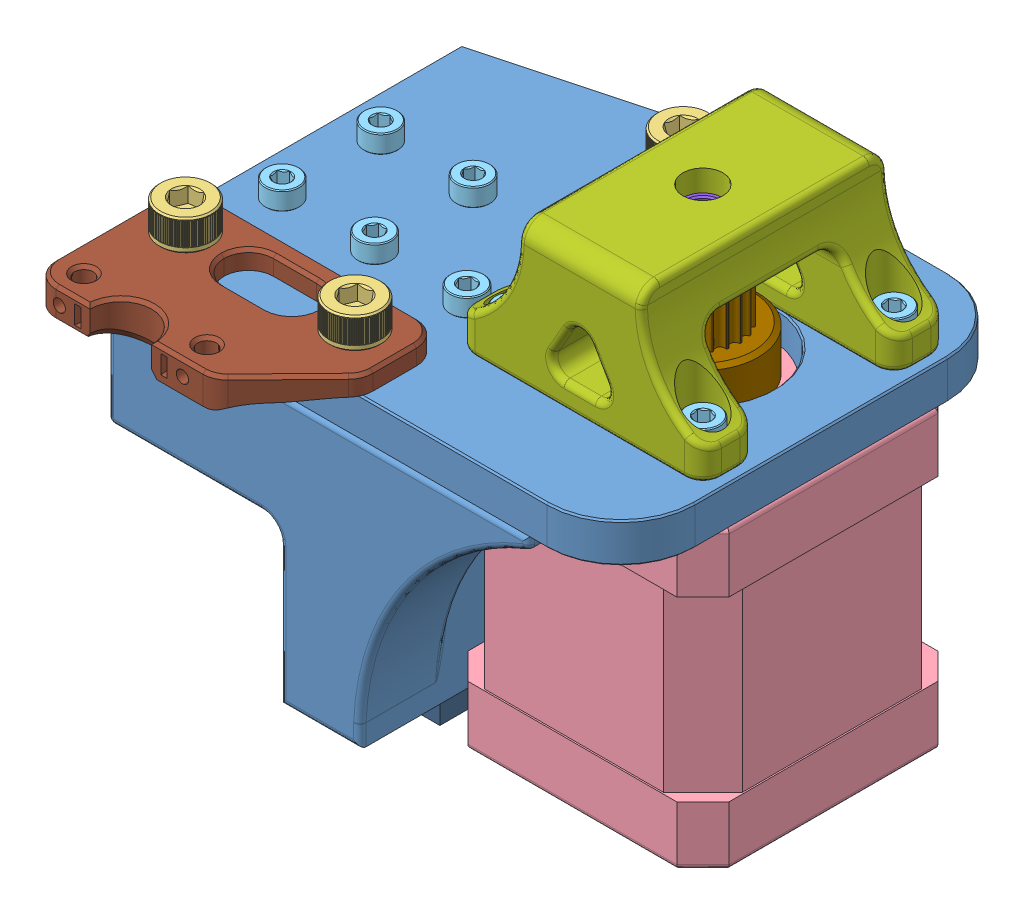
SolidWorks assembly x_motor, configuration Default. Lengths in mm.
Overall size (83.4 79.09 77.36).
24 component instances, 11 part files, 50 mates.
Components (placement in the parent):
- x_axis_motor_mount-1: x_axis_motor_mount [Default] at (11.6499 65.9812 53.7622) size (83.4 49.95 65.06)
- 94180A361_Tapered Heat-Set Inserts for Plastic-2: 94180A361_Tapered Heat-Set Inserts for Plastic [94180A361] at (18.6499 80.6162 113.0622) x (0.881944 0 0.471354) z (0 1 0) size (8.33 8.33 7.05)
- 94180A361_Tapered Heat-Set Inserts for Plastic-3: 94180A361_Tapered Heat-Set Inserts for Plastic [94180A361] at (46.1499 80.6162 113.0622) x (0.881944 0 0.471354) z (0 1 0) size (8.33 8.33 7.05)
- 94180A361_Tapered Heat-Set Inserts for Plastic-4: 94180A361_Tapered Heat-Set Inserts for Plastic [94180A361] at (46.1499 80.6162 59.7622) x (0.881944 0 0.471354) z (0 1 0) size (8.33 8.33 7.05)
- 91290A231_Alloy Steel Socket Head Screw-4: 91290A231_Alloy Steel Socket Head Screw [91290A231] at (46.1499 85.3312 59.7622) x (-0.423416 0 -0.905935) z (0 1 0) size (8.5 8.5 20.34)
- 6627T91_Stepper Motor-1: 6627T91_Stepper Motor [6627T91] at (73.8499 71.9942 84.2622) x (1 0 0) z (0 1 0) size (42.4 43.16 72.04)
- 91290A572_Black-Oxide Alloy Steel Socket Head Screw-8: 91290A572_Black-Oxide Alloy Steel Socket Head Screw [30] at (33.6499 76.8312 81.3622) x (-0.098871 0 -0.9951) z (0 1 0) size (5.5 5.5 33.14)
- 91290A572_Black-Oxide Alloy Steel Socket Head Screw-9: 91290A572_Black-Oxide Alloy Steel Socket Head Screw [30] at (18.6499 76.8312 81.3622) x (0.520474 0 -0.853877) z (0 1 0) size (5.5 5.5 33.14)
- 94180A331_Tapered Heat-Set Inserts for Plastic-6: 94180A331_Tapered Heat-Set Inserts for Plastic [94180A331] at (46.1499 42.2812 86.2622) x (0.757966 0 -0.652294) z (0 -1 0) size (5.56 5.56 3.99)
- 91290A572_Black-Oxide Alloy Steel Socket Head Screw-13: 91290A572_Black-Oxide Alloy Steel Socket Head Screw [10] at (46.1499 40.8812 86.2622) x (0.101337 0 0.994852) z (0 -1 0) size (5.5 5.5 13.14)
- motor_bearing_support-1: motor_bearing_support [Default] at (73.8499 90.3312 84.2622) x (0 0 -1) z (0 1 0) size (40 40 23)
- 6153K69_Stainless Steel Ball Bearing-2: 6153K69_Stainless Steel Ball Bearing [6153K69] at (73.8499 107.3312 84.2622) x (0.996052 0 -0.088777) z (0 1 0) size (16 16 5)
- 91290A572_Black-Oxide Alloy Steel Socket Head Screw-20: 91290A572_Black-Oxide Alloy Steel Socket Head Screw [30] at (18.6499 76.8312 97.3622) x (0.989261 0 -0.146162) z (0 1 0) size (5.5 5.5 33.14)
- 91290A572_Black-Oxide Alloy Steel Socket Head Screw-21: 91290A572_Black-Oxide Alloy Steel Socket Head Screw [30] at (33.6499 76.8312 97.3622) x (0.062138 0 -0.998068) z (0 1 0) size (5.5 5.5 33.14)
- 91290A572_Black-Oxide Alloy Steel Socket Head Screw-22: 91290A572_Black-Oxide Alloy Steel Socket Head Screw [30] at (48.6498 76.8312 97.3622) x (0.062138 0 -0.998068) z (0 1 0) size (5.5 5.5 33.14)
- 91290A572_Black-Oxide Alloy Steel Socket Head Screw-24: 91290A572_Black-Oxide Alloy Steel Socket Head Screw [15mm] at (89.3499 87.3312 68.7622) x (-0.351895 0 0.936039) z (0 1 0) size (5.5 5.5 18.14)
- 91290A572_Black-Oxide Alloy Steel Socket Head Screw-25: 91290A572_Black-Oxide Alloy Steel Socket Head Screw [15mm] at (58.3499 87.3312 68.7622) x (-0.351895 0 0.936039) z (0 1 0) size (5.5 5.5 18.14)
- 91290A572_Black-Oxide Alloy Steel Socket Head Screw-26: 91290A572_Black-Oxide Alloy Steel Socket Head Screw [15mm] at (89.3499 87.3312 99.7622) x (-0.351895 0 0.936039) z (0 1 0) size (5.5 5.5 18.14)
- 91290A572_Black-Oxide Alloy Steel Socket Head Screw-27: 91290A572_Black-Oxide Alloy Steel Socket Head Screw [15mm] at (58.3499 87.3312 99.7622) x (-0.351895 0 0.936039) z (0 1 0) size (5.5 5.5 18.14)
- 3684N13_Corrosion-Resistant HTD Timing Belt Pulley-1: 3684N13_Corrosion-Resistant HTD Timing Belt Pulley [3684N13] at (73.8499 94.0132 84.2622) x (-0.88266 0 0.470012) z (0 1 0) size (18 18 18)
- belp_grip-3: belp_grip [Default] at (46.1499 37.3812 86.2622) x (0 0 1) z (-1 0 0) size (39 3 13)
- y_axis_strain_relief-1: y_axis_strain_relief [Default] at (11.6499 90.3312 106.0622) size (41.5 9.35 25)
- 91290A231_Alloy Steel Socket Head Screw-10: 91290A231_Alloy Steel Socket Head Screw [91290A231] at (18.6499 88.3312 113.0622) x (0.923345 0 0.38397) z (0 1 0) size (8.5 8.5 20.34)
- 91290A231_Alloy Steel Socket Head Screw-11: 91290A231_Alloy Steel Socket Head Screw [91290A231] at (46.1499 88.3312 113.0622) x (0.923345 0 0.38397) z (0 1 0) size (8.5 8.5 20.34)
Mates (geometry in assembly coordinates):
- Concentric11: concentric aligned: cylinder of x_axis_motor_mount-1 through (18.6499 71.9812 113.0622) axis (0 1 0) radius 3.25; cylinder of 94180A361_Tapered Heat-Set Inserts for Plastic-2 through (18.6499 83.9812 113.0622) axis (0 1 0) radius 4.165
- Coincident11: coincident aligned: plane of x_axis_motor_mount-1 through (80.0499 83.9812 105.4622) normal (0 1 0); plane of 94180A361_Tapered Heat-Set Inserts for Plastic-2 through (19.8283 83.9812 110.8573) normal (0 1 0)
- Concentric21: concentric aligned: cylinder of x_axis_motor_mount-1 through (46.1499 71.9812 113.0622) axis (0 1 0) radius 3.25; cylinder of 94180A361_Tapered Heat-Set Inserts for Plastic-3 through (46.1499 83.9812 113.0622) axis (0 1 0) radius 4.165
- Coincident21: coincident aligned: plane of x_axis_motor_mount-1 through (80.0499 83.9812 105.4622) normal (0 1 0); plane of 94180A361_Tapered Heat-Set Inserts for Plastic-3 through (47.3283 83.9812 110.8573) normal (0 1 0)
- Concentric31: concentric aligned: cylinder of x_axis_motor_mount-1 through (46.1499 71.9812 59.7622) axis (0 1 0) radius 3.25; cylinder of 94180A361_Tapered Heat-Set Inserts for Plastic-4 through (46.1499 83.9812 59.7622) axis (0 1 0) radius 4.165
- Coincident31: coincident aligned: plane of x_axis_motor_mount-1 through (80.0499 83.9812 105.4622) normal (0 1 0); plane of 94180A361_Tapered Heat-Set Inserts for Plastic-4 through (47.3283 83.9812 57.5573) normal (0 1 0)
- Coincident61: coincident anti-aligned: plane of x_axis_motor_mount-1 through (11.6499 90.3312 53.7622) normal (0 1 0); plane of 91290A231_Alloy Steel Socket Head Screw-4 through (47.8436 90.3312 63.3859) normal (0 -1 0)
- Concentric7: concentric aligned: cylinder of x_axis_motor_mount-1 through (73.8499 90.3312 84.2622) axis (0 -1 0) radius 11.5; cylinder of 6627T91_Stepper Motor-1 through (73.8499 86.0132 84.2622) axis (0 -1 0) radius 10.985
- Concentric8: concentric aligned: cylinder of x_axis_motor_mount-1 through (89.3499 90.3312 99.7622) axis (0 -1 0) radius 1.5; circle of 6627T91_Stepper Motor-1
- Coincident7: coincident anti-aligned: plane of x_axis_motor_mount-1 through (80.0499 83.9812 105.4622) normal (0 -1 0); plane of 6627T91_Stepper Motor-1 through (73.8499 83.9812 84.2622) normal (0 1 0)
- Coincident141: coincident anti-aligned: plane of x_axis_motor_mount-1 through (11.6499 90.3312 53.7622) normal (0 1 0); plane of 91290A572_Black-Oxide Alloy Steel Socket Head Screw-8 through (31.0626 90.3312 81.6192) normal (0 -1 0)
- Coincident151: coincident anti-aligned: plane of x_axis_motor_mount-1 through (11.6499 90.3312 53.7622) normal (0 1 0); plane of 91290A572_Black-Oxide Alloy Steel Socket Head Screw-9 through (16.4298 90.3312 80.0089) normal (0 -1 0)
- Concentric201: concentric aligned: cylinder of x_axis_motor_mount-1 through (46.1499 45.3812 86.2622) axis (0 -1 0) radius 2; cylinder of 94180A331_Tapered Heat-Set Inserts for Plastic-6 through (46.1499 40.3812 86.2622) axis (0 -1 0) radius 2.78
- Coincident221: coincident aligned: plane of x_axis_motor_mount-1 through (52.6499 40.3812 118.7622) normal (0 -1 0); plane of 94180A331_Tapered Heat-Set Inserts for Plastic-6 through (47.1283 40.3812 87.3991) normal (0 -1 0)
- Coincident274: coincident anti-aligned: plane of x_axis_motor_mount-1 through (11.6499 90.3312 53.7622) normal (0 1 0); plane of motor_bearing_support-1 through (73.8499 90.3312 84.2622) normal (0 -1 0)
- Concentric233: concentric anti-aligned: cylinder of x_axis_motor_mount-1 through (58.3499 90.3312 68.7622) axis (0 -1 0) radius 1.5; cylinder of motor_bearing_support-1 through (58.3499 90.3312 68.7622) axis (0 1 0) radius 1.5
- Concentric234: concentric anti-aligned: cylinder of x_axis_motor_mount-1 through (58.3499 90.3312 99.7622) axis (0 -1 0) radius 1.5; cylinder of motor_bearing_support-1 through (58.3499 90.3312 99.7622) axis (0 1 0) radius 1.5
- Coincident2782: coincident anti-aligned: plane of motor_bearing_support-1 through (73.8499 109.8312 84.2622) normal (0 -1 0); plane of 6153K69_Stainless Steel Ball Bearing-2 through (73.4268 109.8312 79.5145) normal (0 1 0)
- Concentric2382: concentric anti-aligned: cylinder of motor_bearing_support-1 through (73.8499 109.8312 84.2622) axis (0 -1 0) radius 8; cylinder of 6153K69_Stainless Steel Ball Bearing-2 through (73.8499 109.8312 84.2622) axis (0 1 0) radius 8
- Concentric2384: concentric anti-aligned: circle of 94180A361_Tapered Heat-Set Inserts for Plastic-4; circle of 91290A231_Alloy Steel Socket Head Screw-4
- Concentric23861: concentric aligned: cone of x_axis_motor_mount-1 through (18.6499 90.0812 97.3622) axis (0 -1 0); cylinder of 91290A572_Black-Oxide Alloy Steel Socket Head Screw-20 through (18.6499 60.3312 97.3622) axis (0 -1 0) radius 1.5
- Coincident27831: coincident anti-aligned: plane of x_axis_motor_mount-1 through (11.6499 90.3312 53.7622) normal (0 1 0); plane of 91290A572_Black-Oxide Alloy Steel Socket Head Screw-20 through (18.2699 90.3312 94.7901) normal (0 -1 0)
- Concentric23871: concentric aligned: cone of x_axis_motor_mount-1 through (33.6499 90.0812 97.3622) axis (0 -1 0); cylinder of 91290A572_Black-Oxide Alloy Steel Socket Head Screw-21 through (33.6499 60.3312 97.3622) axis (0 -1 0) radius 1.5
- Coincident27841: coincident anti-aligned: plane of x_axis_motor_mount-1 through (11.6499 90.3312 53.7622) normal (0 1 0); plane of 91290A572_Black-Oxide Alloy Steel Socket Head Screw-21 through (31.0549 90.3312 97.2006) normal (0 -1 0)
- Concentric23881: concentric aligned: cone of x_axis_motor_mount-1 through (48.6498 90.0812 97.3622) axis (0 -1 0); cylinder of 91290A572_Black-Oxide Alloy Steel Socket Head Screw-22 through (48.6498 60.3312 97.3622) axis (0 -1 0) radius 1.5
- Coincident27851: coincident anti-aligned: plane of x_axis_motor_mount-1 through (11.6499 90.3312 53.7622) normal (0 1 0); plane of 91290A572_Black-Oxide Alloy Steel Socket Head Screw-22 through (46.0548 90.3312 97.2006) normal (0 -1 0)
- Concentric238821: concentric anti-aligned: cylinder of motor_bearing_support-1 through (89.3499 90.3312 68.7622) axis (0 1 0) radius 1.5; cone of 91290A572_Black-Oxide Alloy Steel Socket Head Screw-24 through (89.3499 93.3312 68.7622) axis (0 -1 0)
- Coincident278521: coincident anti-aligned: plane of motor_bearing_support-1 through (73.8499 93.3312 84.2622) normal (0 1 0); plane of 91290A572_Black-Oxide Alloy Steel Socket Head Screw-24 through (91.7836 93.3312 69.6771) normal (0 -1 0)
- Concentric238831: concentric anti-aligned: cylinder of motor_bearing_support-1 through (58.3499 90.3312 68.7622) axis (0 1 0) radius 1.5; cone of 91290A572_Black-Oxide Alloy Steel Socket Head Screw-25 through (58.3499 93.3312 68.7622) axis (0 -1 0)
- Coincident278531: coincident anti-aligned: plane of motor_bearing_support-1 through (73.8499 93.3312 84.2622) normal (0 1 0); plane of 91290A572_Black-Oxide Alloy Steel Socket Head Screw-25 through (60.7836 93.3312 69.6771) normal (0 -1 0)
- Concentric238841: concentric anti-aligned: cylinder of motor_bearing_support-1 through (89.3499 81.1388 99.7622) axis (0 1 0) radius 3.25; cone of 91290A572_Black-Oxide Alloy Steel Socket Head Screw-26 through (89.3499 93.3312 99.7622) axis (0 -1 0)
- Coincident278541: coincident anti-aligned: plane of motor_bearing_support-1 through (73.8499 93.3312 84.2622) normal (0 1 0); plane of 91290A572_Black-Oxide Alloy Steel Socket Head Screw-26 through (91.7836 93.3312 100.6771) normal (0 -1 0)
- Concentric238851: concentric anti-aligned: cylinder of motor_bearing_support-1 through (58.3499 90.3312 99.7622) axis (0 1 0) radius 1.5; cone of 91290A572_Black-Oxide Alloy Steel Socket Head Screw-27 through (58.3499 93.3312 99.7622) axis (0 -1 0)
- Coincident278551: coincident anti-aligned: plane of motor_bearing_support-1 through (73.8499 93.3312 84.2622) normal (0 1 0); plane of 91290A572_Black-Oxide Alloy Steel Socket Head Screw-27 through (60.7836 93.3312 100.6771) normal (0 -1 0)
- Concentric238853: concentric anti-aligned: cylinder of 6627T91_Stepper Motor-1 through (73.8499 108.0132 84.2622) axis (0 -1 0) radius 2.5; cylinder of 3684N13_Corrosion-Resistant HTD Timing Belt Pulley-1 through (73.8499 104.5132 84.2622) axis (0 1 0) radius 2.5
- Coincident278554: coincident aligned: plane of x_axis_motor_mount-1 through (39.6499 40.3812 118.7622) normal (-1 0 0); plane of belp_grip-3 through (39.6499 40.3812 86.2622) normal (-1 0 0)
- Coincident278555: coincident anti-aligned: plane of x_axis_motor_mount-1 through (52.6499 40.3812 118.7622) normal (0 -1 0); plane of belp_grip-3 through (46.1499 40.3812 86.2622) normal (0 1 0)
- Concentric238854: concentric aligned: circle of 94180A331_Tapered Heat-Set Inserts for Plastic-6; cylinder of belp_grip-3 through (46.1499 40.3812 86.2622) axis (0 -1 0) radius 1.65
- Concentric238855: concentric anti-aligned: circle of 91290A572_Black-Oxide Alloy Steel Socket Head Screw-13; circle of belp_grip-3
- Coincident278556: coincident anti-aligned: plane of 91290A572_Black-Oxide Alloy Steel Socket Head Screw-13 through (43.5633 37.3812 86.5257) normal (0 1 0); plane of belp_grip-3 through (46.1499 37.3812 86.2622) normal (0 -1 0)
- Concentric238856: concentric aligned: cylinder of x_axis_motor_mount-1 through (18.6499 90.3312 81.3622) axis (0 -1 0) radius 1.75; cylinder of 91290A572_Black-Oxide Alloy Steel Socket Head Screw-9 through (18.6499 60.3312 81.3622) axis (0 -1 0) radius 1.5
- Concentric238857: concentric aligned: cylinder of x_axis_motor_mount-1 through (33.6499 90.3312 81.3622) axis (0 -1 0) radius 1.75; cylinder of 91290A572_Black-Oxide Alloy Steel Socket Head Screw-8 through (33.6499 60.3312 81.3622) axis (0 -1 0) radius 1.5
- Distance1: distance = 0.5 mm anti-aligned: plane of 3684N13_Corrosion-Resistant HTD Timing Belt Pulley-1 through (78.08 86.5132 92.2061) normal (0 -1 0); plane of 6627T91_Stepper Motor-1 through (73.8499 86.0132 84.2622) normal (0 1 0)
- Coincident278557: coincident anti-aligned: plane of x_axis_motor_mount-1 through (11.6499 90.3312 53.7622) normal (0 1 0); plane of y_axis_strain_relief-1 through (11.6499 90.3312 106.0622) normal (0 -1 0)
- Coincident278558: coincident anti-aligned: plane of x_axis_motor_mount-1 through (11.6499 65.9812 118.7622) normal (0 0 1); plane of y_axis_strain_relief-1 through (-2.1925 90.3312 118.7622) normal (0 0 -1)
- Concentric238860: concentric anti-aligned: cylinder of x_axis_motor_mount-1 through (18.6499 90.3312 113.0622) axis (0 -1 0) radius 2.5; cylinder of y_axis_strain_relief-1 through (18.6499 83.9812 113.0622) axis (0 1 0) radius 2.75
- Concentric2388631: concentric aligned: cone of y_axis_strain_relief-1 through (18.6499 92.8312 113.0622) axis (0 -1 0); cone of 91290A231_Alloy Steel Socket Head Screw-10 through (18.6499 93.3312 113.0622) axis (0 -1 0)
- Coincident2785611: coincident anti-aligned: plane of y_axis_strain_relief-1 through (11.6499 93.3312 106.0622) normal (0 1 0); plane of 91290A231_Alloy Steel Socket Head Screw-10 through (14.9565 93.3312 111.5263) normal (0 -1 0)
- Concentric2388641: concentric aligned: cone of y_axis_strain_relief-1 through (46.1499 92.8312 113.0622) axis (0 -1 0); cone of 91290A231_Alloy Steel Socket Head Screw-11 through (46.1499 93.3312 113.0622) axis (0 -1 0)
- Coincident2785621: coincident anti-aligned: plane of y_axis_strain_relief-1 through (11.6499 93.3312 106.0622) normal (0 1 0); plane of 91290A231_Alloy Steel Socket Head Screw-11 through (42.4565 93.3312 111.5263) normal (0 -1 0)
